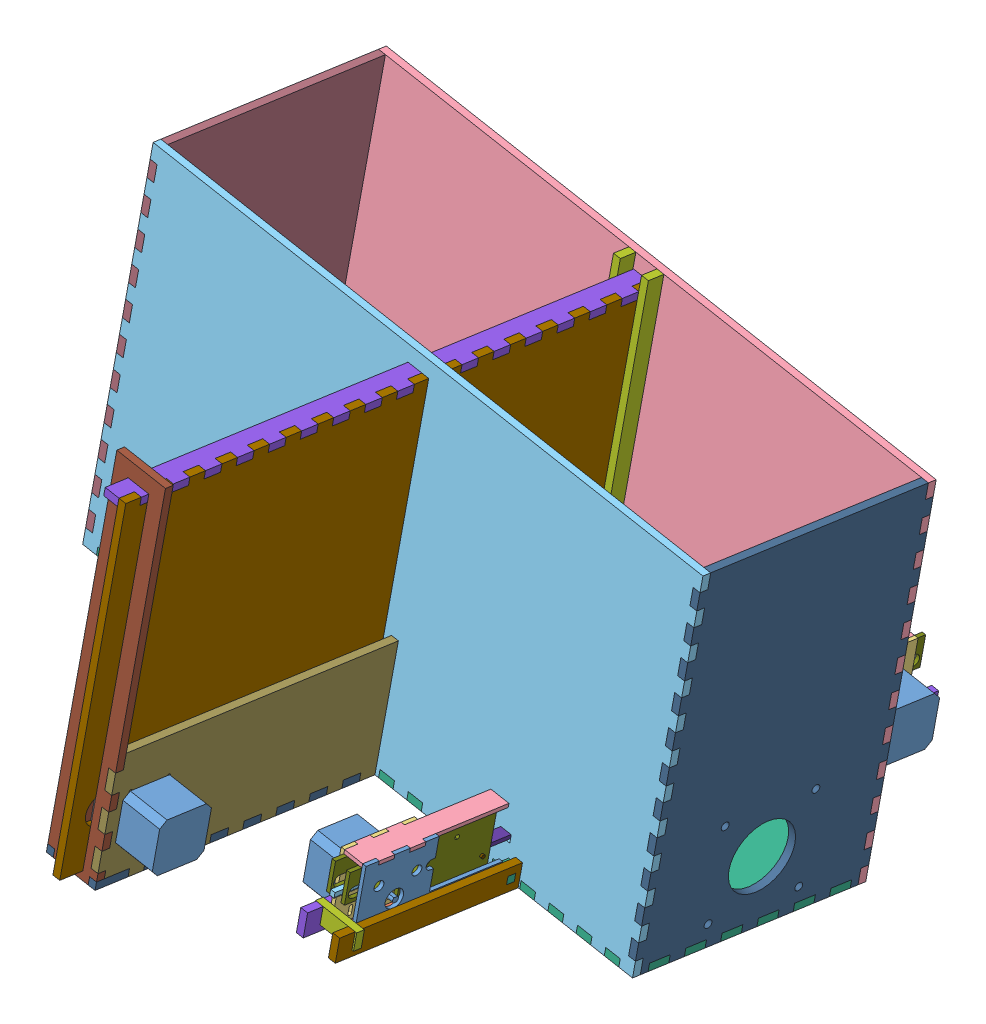
SolidWorks assembly cameraCage, configuration Default. Lengths in mm.
Overall size (548.25 378.82 581.64).
57 component instances, 28 part files, 44 mates.
Components (placement in the parent):
- motor-1: motor [Default] at (-39.1862 -287.453 714.8432) x (0.055055 -0.094132 -0.994036) z (-0.110375 -0.990019 0.087638) size (42.3 58 42.3)
- pinion-1: pinion [Default] at (-55.2148 -285.7588 713.7951) x (-0.082299 -0.954972 -0.285055) z (0.091873 0.277537 -0.956312) size (15 8 14.98)
- rail-1: rail [Default] at (-48.2037 -277.7289 636.5412) x (-0.055055 0.094132 0.994036) z (0.992364 -0.104892 0.064895) size (101.6 4.5 4)
- chamberBack-1: chamberBack [Default] at (-44.3111 -361.0487 427.6762) x (0.992364 -0.104892 0.064895) z (-0.055055 0.094132 0.994036) size (508 304.8 6.35)
- chamberFront-1: chamberFront [Default] at (-44.3111 -361.0487 427.6762) x (0.992364 -0.104892 0.064895) z (-0.055055 0.094132 0.994036) size (508 304.8 6.35)
- chamberBottom-1: chamberBottom [Default] at (-44.3111 -361.0487 427.6762) x (0.992364 -0.104892 0.064895) z (-0.055055 0.094132 0.994036) size (508 6.35 190.5)
- guideFlange-1: guideFlange [Default] at (-19.1431 -215.4423 329.0424) x (0.992364 -0.104892 0.064895) z (-0.055055 0.094132 0.994036) size (6.35 298.45 19.05)
- guideFlange-2: guideFlange [Default] at (-44.8533 -212.7248 327.3611) x (0.992364 -0.104892 0.064895) z (-0.055055 0.094132 0.994036) size (6.35 298.45 19.05)
- doorFlange-2: doorFlange [Default] at (-0.6765 75.1369 516.3251) x (-0.992364 0.104892 -0.064895) z (-0.055055 0.094132 0.994036) size (19.05 6.35 431.8)
- doorSlide-2: doorSlide [Default] at (-31.5153 -201.4743 540.8111) x (-0.992364 0.104892 -0.064895) z (0.055055 -0.094132 -0.994036) size (6.35 285.75 431.8)
- motorMount_bottom-1: motorMount_bottom [Default] at (-45.3064 -183.3006 730.1938) x (0.992364 -0.104892 0.064895) z (-0.055055 0.094132 0.994036) size (44.96 6.35 228.6)
- motorMount_guide-1: motorMount_guide [Default] at (-45.3064 -183.3006 730.1938) x (0.992364 -0.104892 0.064895) z (-0.055055 0.094132 0.994036) size (44.96 304.8 6.35)
- motorMount_mount-1: motorMount_mount [Default] at (-45.3064 -183.3006 730.1938) x (0.992364 -0.104892 0.064895) z (-0.055055 0.094132 0.994036) size (6.35 101.6 234.95)
- chamberLeft-1: chamberLeft [Default] at (-44.3111 -361.0487 427.6762) x (0.992364 -0.104892 0.064895) z (-0.055055 0.094132 0.994036) size (6.35 304.8 190.5)
- leverSupport-1: leverSupport [Default] at (29.8543 -306.1538 662.6384) x (-0.055055 0.094132 0.994036) z (0.992364 -0.104892 0.064895) size (155.7 62.02 64.69)
  - D2RV_L13-1: D2RV_L13 [Default] at (-66.0431 0.3914 47.3736) size (146.17 62.02 58)
    - D2RV_L13_BASE-1: D2RV_L13_BASE [Default] at origin size (37.8 17.39 10.3)
    - D2RV_L13_ACTUATOR-1: D2RV_L13_ACTUATOR [Default] at (-8.6 2.8 -0.2) x (0.996735 0.080744 0) z (0 0 1) size (28.5 9 4.3)
    - leverMount-1: leverMount [Default] at (-23.075 10.5375 5.15) x (0 0 1) z (-1 0 0) size (3.17 55.68 119.5)
    - secondLever-1: secondLever [Default] at (-22.47 11.3875 4.5625) x (0 0 -1) z (-1 0 0) size (9.53 6.35 57.15)
    - Pin-1: Pin [Default] at (-46.6 12.975 -9.0425) x (0.883639 -0.468168 0) z (0 0 1) size (3.07 3.07 19.05)
    - leverMount-2: leverMount [Default] at (-23.075 10.5375 -8.325) x (0 0 1) z (-1 0 0) size (3.17 55.68 119.5)
    - motor-1: motor [Default] at (27.075 15.4 -11.5) x (1 0 0) z (0 1 0) size (42.3 58 42.3)
    - pinion-1: pinion [Default] at (27.075 15.4 -4.4788) x (0.997942 0.064122 0) z (0.064122 -0.997942 0) size (15 8 14.98)
    - leverMotorMount2-1: leverMotorMount2 [Default] at (-7.509 15.7619 15.6501) x (0 0 1) z (1 0 0) size (23 62.02 119.5)
      - leverMotorMount_Right-1: leverMotorMount_Right [Default] at (-15.6501 -25.7881 -55.041) size (3.17 62.02 119.5)
      - leverMotorMount_Bottom-1: leverMotorMount_Bottom [Default] at (-15.6501 -25.7881 -55.041) size (23 3.17 119.5)
      - leverMotorMount_Left-1: leverMotorMount_Left [Default] at (-15.6501 -25.7881 -55.041) size (3.17 62.02 119.5)
      - leverMotorMount_Top-1: leverMotorMount_Top [Default] at (-15.6501 -25.7881 -55.041) size (23 3.17 119.5)
    - railSmall-1: railSmall [Default] at (6.8 3.9 -1.15) size (59.75 4.5 4)
  - leverSupportStop-1: leverSupportStop [Default] at (-135.0771 32.4164 35.6326) x (1 0 0) z (0 1 0) size (6.35 7.94 19.05)
  - leverSupportStop-2: leverSupportStop [Default] at (-135.0771 32.4164 58.8736) x (1 0 0) z (0 -1 0) size (6.35 7.94 19.05)
  - leverSupportEndstop-1: leverSupportEndstop [Default] at (-9.0931 29.8764 47.5169) size (6.35 13.97 38.1)
  - leverSupportLeft-1: leverSupportLeft [Default] at (-68.9101 41.9414 47.2531) x (0 0 1) z (1 0 0) size (6.35 19.05 155.7)
  - leverSupportRight-1: leverSupportRight [Default] at (-68.9101 41.9414 47.2531) x (0 0 1) z (1 0 0) size (6.35 19.05 155.7)
- leverSupport-2: leverSupport [Default] at (149.4756 -360.2417 202.2799) x (0.055055 -0.094132 -0.994036) z (-0.992364 0.104892 -0.064895) size (155.7 62.02 64.69)
  - D2RV_L13-1: D2RV_L13 [Default] at (-66.0431 0.3914 47.3736) size (146.17 62.02 58)
    - D2RV_L13_BASE-1: D2RV_L13_BASE [Default] at origin size (37.8 17.39 10.3)
    - D2RV_L13_ACTUATOR-1: D2RV_L13_ACTUATOR [Default] at (-8.6 2.8 -0.2) x (0.996735 0.080744 0) z (0 0 1) size (28.5 9 4.3)
    - leverMount-1: leverMount [Default] at (-23.075 10.5375 5.15) x (0 0 1) z (-1 0 0) size (3.17 55.68 119.5)
    - secondLever-1: secondLever [Default] at (-22.47 11.3875 4.5625) x (0 0 -1) z (-1 0 0) size (9.53 6.35 57.15)
    - Pin-1: Pin [Default] at (-46.6 12.975 -9.0425) x (0.883639 -0.468168 0) z (0 0 1) size (3.07 3.07 19.05)
    - leverMount-2: leverMount [Default] at (-23.075 10.5375 -8.325) x (0 0 1) z (-1 0 0) size (3.17 55.68 119.5)
    - motor-1: motor [Default] at (27.075 15.4 -11.5) x (1 0 0) z (0 1 0) size (42.3 58 42.3)
    - pinion-1: pinion [Default] at (27.075 15.4 -4.4788) x (0.997942 0.064122 0) z (0.064122 -0.997942 0) size (15 8 14.98)
    - leverMotorMount2-1: leverMotorMount2 [Default] at (-7.509 15.7619 15.6501) x (0 0 1) z (1 0 0) size (23 62.02 119.5)
      - leverMotorMount_Right-1: leverMotorMount_Right [Default] at (-15.6501 -25.7881 -55.041) size (3.17 62.02 119.5)
      - leverMotorMount_Bottom-1: leverMotorMount_Bottom [Default] at (-15.6501 -25.7881 -55.041) size (23 3.17 119.5)
      - leverMotorMount_Left-1: leverMotorMount_Left [Default] at (-15.6501 -25.7881 -55.041) size (3.17 62.02 119.5)
      - leverMotorMount_Top-1: leverMotorMount_Top [Default] at (-15.6501 -25.7881 -55.041) size (23 3.17 119.5)
    - railSmall-1: railSmall [Default] at (6.8 3.9 -1.15) size (59.75 4.5 4)
  - leverSupportStop-1: leverSupportStop [Default] at (-135.0771 32.4164 35.6326) x (1 0 0) z (0 1 0) size (6.35 7.94 19.05)
  - leverSupportStop-2: leverSupportStop [Default] at (-135.0771 32.4164 58.8736) x (1 0 0) z (0 -1 0) size (6.35 7.94 19.05)
  - leverSupportEndstop-1: leverSupportEndstop [Default] at (-9.0931 29.8764 47.5169) size (6.35 13.97 38.1)
  - leverSupportLeft-1: leverSupportLeft [Default] at (-68.9101 41.9414 47.2531) x (0 0 1) z (1 0 0) size (6.35 19.05 155.7)
  - leverSupportRight-1: leverSupportRight [Default] at (-68.9101 41.9414 47.2531) x (0 0 1) z (1 0 0) size (6.35 19.05 155.7)
- chamberRight-1: chamberRight [Default] at (453.5082 -413.6677 460.231) x (0.992364 -0.104892 0.064895) z (-0.055055 0.094132 0.994036) size (6.35 304.8 190.5)
Mates (geometry in assembly coordinates):
- Concentric1: concentric: cylinder of motor-1 through (-63.003 -284.9356 713.2857) axis (0.992364 -0.104892 0.064895) radius 2.396; cylinder of pinion-1 through (-50.252 -286.2834 714.1196) axis (-0.992364 0.104892 -0.064895) radius 2.5
- Coincident15: coincident: plane of chamberBack-1 through (-43.6103 -354.7621 427.1197) normal (-0.110375 -0.990019 0.087638); plane of chamberBottom-1 through (-43.6103 -354.7621 427.1197) normal (0.110375 0.990019 -0.087638)
- Coincident16: coincident: plane of chamberBack-1 through (-290.4267 -337.0855 315.9543) normal (0.055055 -0.094132 -0.994036); plane of chamberBottom-1 through (-290.4267 -337.0855 315.9543) normal (0.055055 -0.094132 -0.994036)
- Coincident18: coincident: plane of chamberBack-1 through (195.8472 -380.0725 442.7789) normal (-0.992364 0.104892 -0.064895); plane of chamberBottom-1 through (195.8472 -380.0725 442.7789) normal (0.992364 -0.104892 0.064895)
- Coincident25: coincident: plane of chamberFront-1 through (-43.6103 -354.7621 427.1197) normal (-0.110375 -0.990019 0.087638); plane of chamberBottom-1 through (-43.6103 -354.7621 427.1197) normal (0.110375 0.990019 -0.087638)
- Coincident33: coincident: plane of chamberBack-1 through (-61.5005 -367.6436 331.5262) normal (0.992364 -0.104892 0.064895); plane of guideFlange-2 through (-44.8533 -212.7248 327.3611) normal (-0.992364 0.104892 -0.064895)
- Coincident34: coincident: plane of chamberBottom-1 through (-43.6103 -354.7621 427.1197) normal (0.110375 0.990019 -0.087638); plane of guideFlange-2 through (-55.0225 -361.1264 340.851) normal (-0.110375 -0.990019 0.087638)
- Coincident36: coincident: plane of guideFlange-1 through (-29.3124 -363.8439 342.5323) normal (-0.110375 -0.990019 0.087638); plane of chamberBottom-1 through (-43.6103 -354.7621 427.1197) normal (0.110375 0.990019 -0.087638)
- Coincident37: coincident: plane of chamberBack-1 through (-35.7903 -370.3612 333.2075) normal (0.992364 -0.104892 0.064895); plane of guideFlange-1 through (-19.1431 -215.4423 329.0424) normal (-0.992364 0.104892 -0.064895)
- Coincident38: coincident: plane of chamberBack-1 through (-290.4267 -337.0855 315.9543) normal (0.055055 -0.094132 -0.994036); plane of guideFlange-2 through (-38.0274 -214.2874 318.305) normal (0.055055 -0.094132 -0.994036)
- Coincident39: coincident: plane of chamberBack-1 through (-290.4267 -337.0855 315.9543) normal (0.055055 -0.094132 -0.994036); plane of guideFlange-1 through (-12.3172 -217.005 319.9863) normal (0.055055 -0.094132 -0.994036)
- Coincident52: coincident: plane of doorFlange-2 through (-34.6343 -45.323 743.0467) normal (-0.110375 -0.990019 0.087638); plane of doorSlide-2 through (-22.7479 -65.646 528.4343) normal (0.110375 0.990019 -0.087638)
- Coincident53: coincident: plane of doorFlange-2 through (-34.6343 -45.323 743.0467) normal (-0.055055 0.094132 0.994036); plane of doorSlide-2 through (-33.9334 -39.0364 742.4902) normal (-0.055055 0.094132 0.994036)
- Coincident54: coincident: plane of doorFlange-2 through (-6.978 75.8029 515.913) normal (0.992364 -0.104892 0.064895); plane of doorSlide-2 through (-37.8168 -200.8083 540.399) normal (-0.992364 0.104892 -0.064895)
- Coincident55: coincident: plane of chamberFront-1 through (-13.3106 -64.1886 484.3269) normal (-0.110375 -0.990019 0.087638); plane of doorFlange-2 through (-46.5364 -37.7042 741.666) normal (0.110375 0.990019 -0.087638)
- Coincident56: coincident: plane of chamberFront-1 through (-13.3106 -64.1886 484.3269) normal (-0.992364 0.104892 -0.064895); plane of doorSlide-2 through (-31.5153 -201.4743 540.8111) normal (0.992364 -0.104892 0.064895)
- Coincident57: coincident: plane of rail-1 through (-48.2037 -277.7289 636.5412) normal (0.110375 0.990019 -0.087638); plane of doorSlide-2 through (-70.3698 -266.4134 736.4515) normal (-0.110375 -0.990019 0.087638)
- Coincident58: coincident: plane of rail-1 through (-52.6698 -281.7644 636.676) normal (-0.992364 0.104892 -0.064895); plane of doorSlide-2 through (-37.8168 -200.8083 540.399) normal (-0.992364 0.104892 -0.064895)
- Coincident65: coincident: plane of motorMount_guide-1 through (-45.3064 -183.3006 730.1938) normal (0.055055 -0.094132 -0.994036); plane of motorMount_mount-1 through (-45.3064 -183.3006 730.1938) normal (-0.055055 0.094132 0.994036)
- Coincident66: coincident: plane of motorMount_guide-1 through (-12.6186 -30.485 723.9213) normal (0.992364 -0.104892 0.064895); plane of motorMount_mount-1 through (-12.6186 -30.485 723.9213) normal (0.992364 -0.104892 0.064895)
- Coincident67: coincident: plane of motorMount_guide-1 through (-90.8757 -327.5269 747.7157) normal (-0.110375 -0.990019 0.087638); plane of motorMount_mount-1 through (-90.8757 -327.5269 747.7157) normal (-0.110375 -0.990019 0.087638)
- Coincident68: coincident: plane of motorMount_bottom-1 through (-64.7167 -323.9312 748.8241) normal (0.110375 0.990019 -0.087638); plane of motorMount_mount-1 through (-61.0903 -324.8753 742.7262) normal (-0.110375 -0.990019 0.087638)
- Coincident69: coincident: plane of motorMount_bottom-1 through (-45.656 -182.7029 736.5059) normal (-0.055055 0.094132 0.994036); plane of motorMount_guide-1 through (-45.656 -182.7029 736.5059) normal (-0.055055 0.094132 0.994036)
- Coincident72: coincident: plane of motorMount_bottom-1 through (-12.6186 -30.485 723.9213) normal (0.992364 -0.104892 0.064895); plane of motorMount_mount-1 through (-12.6186 -30.485 723.9213) normal (0.992364 -0.104892 0.064895)
- Coincident73: coincident: plane of chamberFront-1 through (-29.4653 -266.2779 502.5692) normal (0.992364 -0.104892 0.064895); plane of motorMount_mount-1 through (-35.7281 -184.3131 730.8202) normal (-0.992364 0.104892 -0.064895)
- Coincident74: coincident: plane of chamberBottom-1 through (-44.3111 -361.0487 427.6762) normal (-0.110375 -0.990019 0.087638); plane of motorMount_bottom-1 through (-90.8757 -327.5269 747.7157) normal (-0.110375 -0.990019 0.087638)
- Coincident75: coincident: plane of chamberFront-1 through (-261.3222 -24.9462 473.2626) normal (0.055055 -0.094132 -0.994036); plane of motorMount_mount-1 through (-23.1425 -205.8315 503.5835) normal (0.055055 -0.094132 -0.994036)
- Coincident76: coincident: plane of motor-1 through (-39.1862 -287.453 714.8432) normal (-0.992364 0.104892 -0.064895); plane of motorMount_mount-1 through (-12.6186 -30.485 723.9213) normal (0.992364 -0.104892 0.064895)
- Tangent1: tangent: cylinder of motor-1 through (-41.171 -287.2433 714.7134) axis (0.992364 -0.104892 0.064895) radius 11; plane of motorMount_mount-1 through (-33.7241 -187.7395 694.6373) normal (-0.055055 0.094132 0.994036)
- Tangent2: tangent: cylinder of motor-1 through (-41.171 -287.2433 714.7134) axis (0.992364 -0.104892 0.064895) radius 11; plane of motorMount_mount-1 through (-34.9353 -185.6686 716.5061) normal (0.055055 -0.094132 -0.994036)
- Coincident79: coincident: axis of motor-1 through (-35.5781 -304.7294 701.0861) axis (-0.992364 0.104892 -0.064895); axis of motorMount_mount-1 through (-46.3452 -303.5913 700.382) axis (0.992364 -0.104892 0.064895)
- Coincident80: coincident: point of rail-1; point of doorSlide-2
- Coincident81: coincident: plane of chamberFront-1 through (-261.3222 -24.9462 473.2626) normal (0.055055 -0.094132 -0.994036); plane of chamberLeft-1 through (-262.7239 -37.5194 474.3756) normal (-0.055055 0.094132 0.994036)
- Coincident82: coincident: plane of chamberBack-1 through (-290.0701 -335.0722 411.6048) normal (-0.992364 0.104892 -0.064895); plane of chamberLeft-1 through (-251.5333 -41.6828 296.523) normal (0.992364 -0.104892 0.064895)
- Coincident83: coincident: plane of chamberBottom-1 through (-43.6103 -354.7621 427.1197) normal (0.110375 0.990019 -0.087638); plane of chamberLeft-1 through (-43.6103 -354.7621 427.1197) normal (-0.110375 -0.990019 0.087638)
- Coincident84: coincident: plane of chamberBottom-1 through (-44.3111 -361.0487 427.6762) normal (-0.110375 -0.990019 0.087638); plane of leverSupport-1/leverSupportRight-1 through (75.9111 -359.1196 600.8814) normal (-0.110375 -0.990019 0.087638)
- Coincident85: coincident: plane of chamberFront-1 through (100.0772 -349.3773 524.0013) normal (-0.992364 0.104892 -0.064895); plane of leverSupport-1/leverSupportRight-1 through (100.0772 -349.3773 524.0013) normal (0.992364 -0.104892 0.064895)
- Coincident86: coincident: plane of chamberFront-1 through (-261.3222 -24.9462 473.2626) normal (0.055055 -0.094132 -0.994036); plane of leverSupport-1/leverSupportRight-1 through (93.7757 -348.7113 523.5892) normal (0.055055 -0.094132 -0.994036)
- Coincident87: coincident: plane of chamberBottom-1 through (-44.3111 -361.0487 427.6762) normal (-0.110375 -0.990019 0.087638); plane of leverSupport-2/leverSupportLeft-1 through (94.1602 -390.3214 271.3882) normal (-0.110375 -0.990019 0.087638)
- Coincident88: coincident: plane of chamberBack-1 through (80.501 -363.0101 345.3413) normal (-0.992364 0.104892 -0.064895); plane of leverSupport-2/leverSupportRight-1 through (81.4379 -364.612 328.4248) normal (0.992364 -0.104892 0.064895)
- Coincident89: coincident: plane of chamberBack-1 through (-251.5333 -41.6828 296.523) normal (-0.055055 0.094132 0.994036); plane of leverSupport-2/leverSupportLeft-1 through (109.866 -366.1139 347.2617) normal (-0.055055 0.094132 0.994036)
- Coincident90: coincident: plane of chamberFront-1 through (-261.3222 -24.9462 473.2626) normal (0.055055 -0.094132 -0.994036); plane of chamberRight-1 through (235.0955 -90.1385 506.9304) normal (-0.055055 0.094132 0.994036)
- Coincident91: coincident: plane of chamberFront-1 through (213.6942 -390.3706 348.9212) normal (0.992364 -0.104892 0.064895); plane of chamberRight-1 through (246.286 -94.3018 329.0778) normal (0.992364 -0.104892 0.064895)
- Coincident92: coincident: plane of chamberBack-1 through (-10.6688 -59.291 400.9641) normal (0.110375 0.990019 -0.087638); plane of chamberRight-1 through (487.1506 -111.91 433.5189) normal (0.110375 0.990019 -0.087638)
